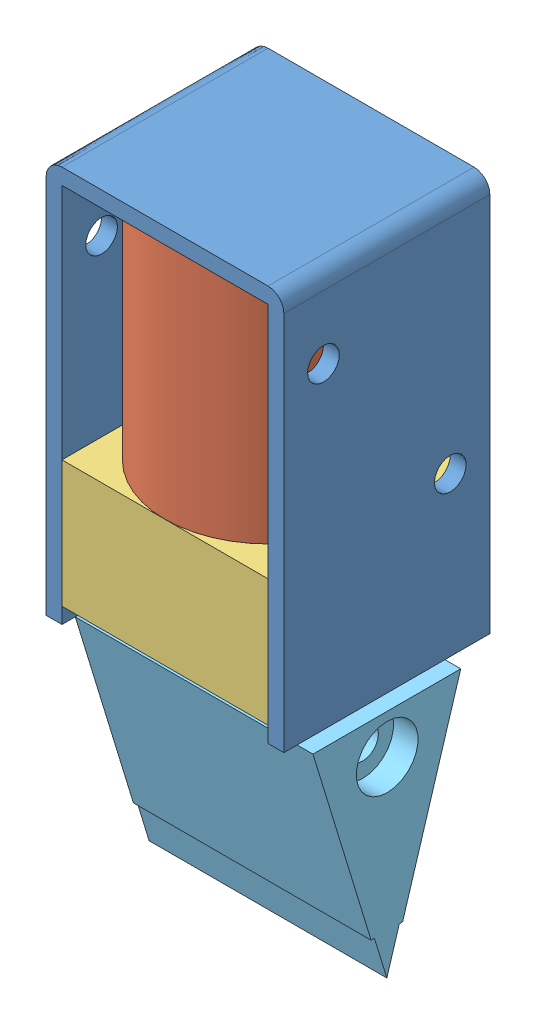
SolidWorks assembly Solenoid, configuration Default. Lengths in mm.
Overall size (15 40.57 13).
5 component instances, 5 part files, 10 mates.
Components (placement in the parent):
- External part-1: External part [Default] at (4.8787 9.4049 13.8573) x (0 -1 0) z (0 0 1) size (25 15 13)
- Coil-2: Coil [Default] at (-2.6213 18.4049 20.3573) size (13 15 13)
- Front-1: Front [Default] at (3.8787 18.4049 13.8573) x (0 0 1) z (0 -1 0) size (13 13 8)
- Plunger Solenoid-1: Plunger Solenoid [Default] at (-2.6213 28.4049 20.3573) x (0 -1 0) z (0 0 1) size (25 6 6)
- Solenoid Insert Verowhite-1: Solenoid Insert Verowhite [Default] at (-7.6213 12.9703 20.3372) x (0 0 -1) z (0 -1 0) size (9.32 15 14.57)
Mates (geometry in assembly coordinates):
- Coincident4: coincident anti-aligned: plane of External part-1 through (4.8787 33.4049 26.8573) normal (0 -1 0); plane of Coil-2 through (-2.6213 33.4049 20.3573) normal (0 1 0)
- Coincident9: coincident anti-aligned: plane of Coil-2 through (-2.6213 18.4049 20.3573) normal (0 -1 0); plane of Front-1 through (3.8787 18.4049 13.8573) normal (0 1 0)
- Coincident11: coincident anti-aligned: plane of External part-1 through (3.8787 9.4049 26.8573) normal (-1 0 0); plane of Front-1 through (3.8787 10.4049 13.8573) normal (1 0 0)
- Distance2: distance = 0 mm aligned: plane of Front-1 through (3.8787 10.4049 13.8573) normal (0 0 -1); plane of External part-1 through (4.8787 9.4049 13.8573) normal (0 0 -1)
- Concentric1: concentric anti-aligned: cylinder of Front-1 through (-2.6213 18.4049 20.3573) axis (0 -1 0) radius 3; cylinder of Plunger Solenoid-1 through (-2.6213 3.4049 20.3573) axis (0 1 0) radius 3
- Concentric2: concentric aligned: cylinder of Coil-2 through (-2.6213 28.4049 20.3573) axis (0 -1 0) radius 3; cylinder of Front-1 through (-2.6213 18.4049 20.3573) axis (0 -1 0) radius 3
- LimitDistance1: limit distance = 0 mm anti-aligned: plane of Coil-2 through (-2.6213 28.4049 20.3573) normal (0 -1 0); plane of Plunger Solenoid-1 through (-2.6213 28.4049 20.3573) normal (0 1 0)
- Concentric3: concentric aligned: cylinder of Plunger Solenoid-1 through (-2.6213 3.4049 20.3573) axis (0 1 0) radius 3; cylinder of Solenoid Insert Verowhite-1 through (-2.6213 12.4859 26.2582) axis (0 1 0) radius 3.05
- Coincident12: coincident anti-aligned: plane of Plunger Solenoid-1 through (-2.6213 3.4049 20.3573) normal (0 -1 0); plane of Solenoid Insert Verowhite-1 through (-2.6213 12.4859 26.2582) normal (0 1 0)
- Parallel2: parallel aligned: plane of External part-1 through (4.8787 9.4049 26.8573) normal (1 0 0); plane of Solenoid Insert Verowhite-1
